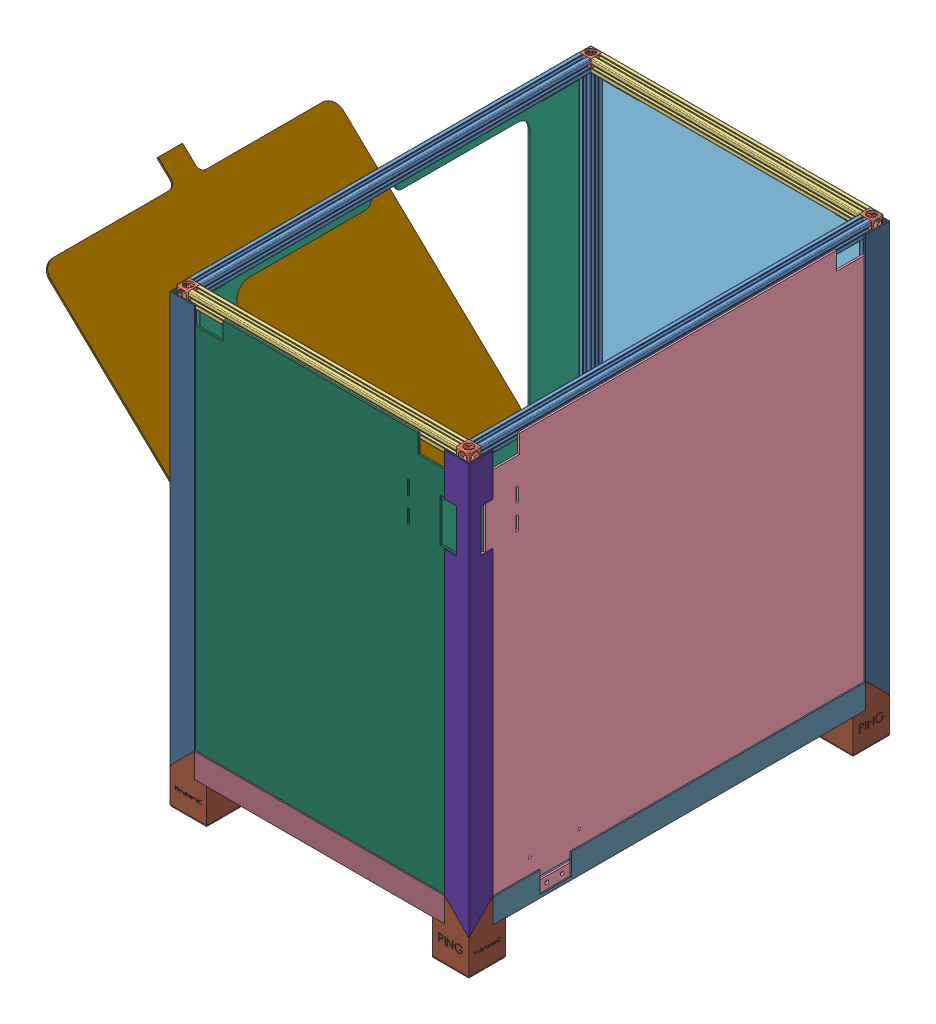
SolidWorks assembly carcasse, configuration Défaut. Lengths in mm.
Overall size (836.58 948 690).
62 component instances, 26 part files, 77 mates.
Components (placement in the parent):
- cadre-1: cadre [Défaut] at (-215.194 -19.8636 -400) size (480 20 680)
  - prof_20x20x600mm-1: prof_20x20x600mm [End Finishing_Non-Machined End Finish Options_Type_Single_] at (-14.8937 4.0689 600) size (20 20 640)
  - Blocks-1: Blocks [Défaut] at (-4.8937 14.0689 1240) x (0 1 0) z (0 0 1) size (20 20 20)
  - prof_20x20x600mm-3: prof_20x20x600mm [End Finishing_Non-Machined End Finish Options_Type_Single_] at (445.1063 4.0689 600) size (20 20 640)
  - Blocks-3: Blocks [Défaut] at (-4.8937 -5.9311 580) x (0 0 -1) z (0 1 0) size (20 20 20)
  - Blocks-4: Blocks [Défaut] at (435.1063 14.0689 600) x (0 1 0) z (0 0 -1) size (20 20 20)
  - Blocks-5: Blocks [Défaut] at (435.1063 -5.9311 1260) x (0 0 1) z (0 1 0) size (20 20 20)
  - prof_20x20x400mm-1: prof_20x20x400mm [End Finishing_Non-Machined End Finish Options_Type_Single_] at (435.1063 4.0689 590) x (0 0 1) z (-1 0 0) size (20 20 440)
  - prof_20x20x400mm-2: prof_20x20x400mm [End Finishing_Non-Machined End Finish Options_Type_Single_] at (435.1063 4.0689 1250) x (0 0 1) z (-1 0 0) size (20 20 440)
- prof_20x20x600mm-1: prof_20x20x600mm [End Finishing_Non-Machined End Finish Options_Type_Single_] at (229.9123 -25.7947 190) x (1 0 0) z (0 -1 0) size (20 20 640)
- prof_20x20x600mm-2: prof_20x20x600mm [End Finishing_Non-Machined End Finish Options_Type_Single_] at (229.9123 -25.7947 850) x (1 0 0) z (0 -1 0) size (20 20 640)
- prof_20x20x600mm-3: prof_20x20x600mm [End Finishing_Non-Machined End Finish Options_Type_Single_] at (-230.0877 -25.7947 850) x (1 0 0) z (0 -1 0) size (20 20 640)
- prof_20x20x600mm-4: prof_20x20x600mm [End Finishing_Non-Machined End Finish Options_Type_Single_] at (-230.0877 -25.7947 190) x (1 0 0) z (0 -1 0) size (20 20 640)
- cadre-2: cadre [Défaut] at (215.0186 -671.7258 -400) x (-1 0 0) z (0 0 1) size (480 20 680)
  - prof_20x20x600mm-1: prof_20x20x600mm [End Finishing_Non-Machined End Finish Options_Type_Single_] at (-14.8937 4.0689 600) size (20 20 640)
  - Blocks-1: Blocks [Défaut] at (-4.8937 14.0689 1240) x (0 1 0) z (0 0 1) size (20 20 20)
  - prof_20x20x600mm-3: prof_20x20x600mm [End Finishing_Non-Machined End Finish Options_Type_Single_] at (445.1063 4.0689 600) size (20 20 640)
  - Blocks-3: Blocks [Défaut] at (-4.8937 -5.9311 580) x (0 0 -1) z (0 1 0) size (20 20 20)
  - Blocks-4: Blocks [Défaut] at (435.1063 14.0689 600) x (0 1 0) z (0 0 -1) size (20 20 20)
  - Blocks-5: Blocks [Défaut] at (435.1063 -5.9311 1260) x (0 0 1) z (0 1 0) size (20 20 20)
  - prof_20x20x400mm-1: prof_20x20x400mm [End Finishing_Non-Machined End Finish Options_Type_Single_] at (435.1063 4.0689 590) x (0 0 1) z (-1 0 0) size (20 20 440)
  - prof_20x20x400mm-2: prof_20x20x400mm [End Finishing_Non-Machined End Finish Options_Type_Single_] at (435.1063 4.0689 1250) x (0 0 1) z (-1 0 0) size (20 20 440)
- plaque_acrylique_680x670-2: plaque_acrylique_680x670 [Défaut] at (239.9123 -350.7947 520) x (0 0 -1) z (1 0 0) size (680 670 3)
- plaque_acrylique_380x670_G-1: plaque_acrylique_380x670_G [Défaut] at (49.9123 -350.7947 177) size (480 670 3)
- plaque_acrylique_680x670_porte-1: plaque_acrylique_680x670_porte [Défaut] at (-243.0877 -350.7947 520) x (0 0 -1) z (1 0 0) size (680 670 3)
- charniere-1: charniere [Défaut] at (-236.7309 -495.7947 776.2875) x (0 0 1) z (0 -1 0) size (40 29.08 53.23)
  - axe charnière-1: axe charnière [Défaut] at (-76.2875 9.8568 0) size (40 5 5)
  - batant charnière-1: batant charnière [Défaut] at (-76.2875 10.1991 -17.6196) size (40 7 33.5)
  - batant charnière-2: batant charnière [Défaut] at (-36.2875 -2.6626 12.4029) x (-1 0 0) z (0 0.723942 -0.689861) size (40 7 33.5)
- charniere-2: charniere [Défaut] at (-236.7309 -495.7947 376.2875) x (0 0 1) z (0 -1 0) size (40 29.08 53.23)
  - axe charnière-1: axe charnière [Défaut] at (-76.2875 9.8568 0) size (40 5 5)
  - batant charnière-1: batant charnière [Défaut] at (-76.2875 10.1991 -17.6196) size (40 7 33.5)
  - batant charnière-2: batant charnière [Défaut] at (-36.2875 -2.6626 12.4029) x (-1 0 0) z (0 0.723942 -0.689861) size (40 7 33.5)
- porte-1: porte [Défaut] at (-349.1448 -393.231 520) x (0 0 -1) z (0.689861 0.723942 0) size (480 480 3)
- eclisse_40x40x670_bisote_x1-1: eclisse_40x40x670_bisote_x1 [Défaut] at (-225.0877 -688.7947 195.1136) size (40 673 40)
- eclisse_40x40x670_bisote_x1-2: eclisse_40x40x670_bisote_x1 [Défaut] at (-224.9741 -688.7947 845) x (0 0 -1) z (1 0 0) size (40 673 40)
- eclisse_40x40x670_bisote_x1-4: eclisse_40x40x670_bisote_x1 [Défaut] at (224.7986 -688.7947 195) x (0 0 1) z (-1 0 0) size (40 673 40)
- couvercle-1: couvercle [Défaut] at (451.7811 15.2953 693.3892) size (490 215 690) (hidden)
  - plaque_acrylique_680x210-2: plaque_acrylique_680x210 [Défaut] at (-694.8689 73.91 -173.3892) x (0 0 -1) z (1 0 0) size (680 210 3)
  - plaque_acrylique_380x210-2: plaque_acrylique_380x210 [Défaut] at (-401.8689 73.91 -516.3892) size (480 210 3)
  - plaque_acrylique_380x680-1: plaque_acrylique_380x680 [Défaut] at (-401.8689 178.91 -173.3892) x (1 0 0) z (0 1 0) size (480 680 3)
  - eclisse_40x40x404_bisote_x2-1: eclisse_40x40x404_bisote_x2 [Défaut] at (-206.8689 163.7964 -498.3892) x (0 0 1) z (0 -1 0) size (40 490 40)
  - eclisse_40x40x704_bisote_x2-1: eclisse_40x40x704_bisote_x2 [Défaut] at (-226.9825 163.91 -518.3892) x (0 -1 0) z (-1 0 0) size (40 690 40)
  - eclisse_40x40x404_bisote_x2-2: eclisse_40x40x404_bisote_x2 [Défaut] at (-696.8689 163.7964 151.6108) x (0 0 -1) z (0 -1 0) size (40 490 40)
  - eclisse_40x40x704_bisote_x2-2: eclisse_40x40x704_bisote_x2 [Défaut] at (-676.8689 163.7964 -518.3892) x (1 0 0) z (0 -1 0) size (40 690 40)
  - eclisse_40x40x222_bisote_x1-1: eclisse_40x40x222_bisote_x1 [Défaut] at (-676.7552 183.91 -498.3892) x (0 0 1) z (1 0 0) size (40 215 40)
  - eclisse_40x40x222_bisote_x1-2: eclisse_40x40x222_bisote_x1 [Défaut] at (-226.8689 183.91 -498.2755) x (-1 0 0) z (0 0 1) size (40 215 40)
  - eclisse_40x40x222_bisote_x1-4: eclisse_40x40x222_bisote_x1 [Défaut] at (-676.8689 183.91 151.4972) x (1 0 0) z (0 0 -1) size (40 215 40)
  - plaque_acrylique_380x210_Moteur-1: plaque_acrylique_380x210_Moteur [Défaut] at (-401.8689 73.91 166.6108) size (480 210 3)
  - plaque_acrylique_680x210_moteur-1: plaque_acrylique_680x210_moteur [Défaut] at (-211.8689 73.91 -173.3892) x (0 0 -1) z (1 0 0) size (680 210 3)
  - eclisse_40x40x222_bisote_x1_Moteur-1: eclisse_40x40x222_bisote_x1_Moteur [Défaut] at (-226.9825 183.91 151.6108) x (0 0 -1) z (-1 0 0) size (40 215 40)
- Pied-1: Pied [Défaut] at (184.9123 -688.7947 235) x (-1 0 0) z (0 -1 0) size (60 60 100)
- Pied-2: Pied [Défaut] at (184.9123 -688.7947 805) x (0 0 -1) z (0 -1 0) size (60 60 100)
- Pied-3: Pied [Défaut] at (-185.0877 -688.7947 805) x (1 0 0) z (0 -1 0) size (60 60 100)
- Pied-4: Pied [Défaut] at (-185.0877 -688.7947 235) x (0 0 1) z (0 -1 0) size (60 60 100)
- eclisse_bas_40x40x704-2: eclisse_bas_40x40x704 [Défaut] at (-225.0877 -670.681 825) x (1 0 0) z (0 1 0) size (40 610 40)
- eclisse_bas_40x40x404-1: eclisse_bas_40x40x404 [Défaut] at (-205.0877 -670.681 195) x (0 0 1) z (0 1 0) size (40 410 40)
- eclisse_bas_40x40x404-2: eclisse_bas_40x40x404 [Défaut] at (204.9123 -668.681 845) x (0 0 -1) z (0 1 0) size (40 410 40)
- eclisse_bas_support_Z_40x40x704-1: eclisse_bas_support_Z_40x40x704 [Défaut] at (224.7986 -670.7947 825) x (0 1 0) z (-1 0 0) size (40 610 40)
- plaque_acrylique_380x670_D-2: plaque_acrylique_380x670_D [Défaut] at (-50.0877 -350.7947 863) x (-1 0 0) z (0 0 -1) size (480 670 3)
- plaque_acrylique_bas_380x680-1: plaque_acrylique_bas_380x680 [Défaut] at (49.9123 -688.7947 520) x (1 0 0) z (0 1 0) size (480 680 3)
- eclisse_40x40x670_bisote_x1-Moteur-1: eclisse_40x40x670_bisote_x1-Moteur [Défaut] at (224.9123 -688.7947 844.8864) x (-1 0 0) z (0 0 -1) size (40 673 40)
Mates (geometry in assembly coordinates):
- Coïncidente50: coincident anti-aligned: plane of plaque_acrylique_680x670_porte-1 through (-243.0877 -350.7947 520) normal (-1 0 0); plane of charniere-1/batant charnière-1 through (-243.0877 -535.7947 740) normal (1 0 0)
- Coïncidente51: coincident anti-aligned: plane of plaque_acrylique_680x670_porte-1 through (-243.0877 -350.7947 520) normal (-1 0 0); plane of charniere-2/batant charnière-1 through (-243.0877 -535.7947 340) normal (1 0 0)
- Distance4: distance = 20 mm anti-aligned: plane of charniere-2/batant charnière-1 through (-246.5877 -495.7947 300) normal (0 0 -1); plane of plaque_acrylique_680x670_porte-1 through (-243.0877 -75.7947 280) normal (0 0 1)
- Coïncidente54: coincident aligned: line of plaque_acrylique_680x670_porte-1 through (-243.0877 -495.7947 740) axis (0 0 -1); line of charniere-2/batant charnière-1 through (-243.0877 -495.7947 340) axis (0 0 -1)
- Distance5: distance = 20 mm anti-aligned: plane of plaque_acrylique_680x670_porte-1 through (-243.0877 -75.7947 760) normal (0 0 -1); plane of charniere-1/batant charnière-1 through (-246.5877 -495.7947 740) normal (0 0 1)
- Coïncidente57: coincident aligned: line of plaque_acrylique_680x670_porte-1 through (-243.0877 -495.7947 740) axis (0 0 -1); line of charniere-1/batant charnière-1 through (-243.0877 -495.7947 740) axis (0 0 -1)
- Coïncidente62: coincident anti-aligned: plane of charniere-1/batant charnière-2 through (-273.1309 -465.6664 700) normal (0.689861 0.723942 0); plane of porte-1 through (-569.947 -182.8234 550) normal (-0.689861 -0.723942 0)
- Coïncidente63: coincident anti-aligned: line of charniere-1/batant charnière-2 through (-244.1732 -493.2609 720) axis (0 0 1); line of porte-1 through (-244.1732 -493.2609 740) axis (0 0 -1)
- Coïncidente64: coincident anti-aligned: plane of plaque_acrylique_680x670_porte-1 through (-243.0877 -75.7947 760) normal (0 0 -1); plane of porte-1 through (-546.1592 -201.3474 760) normal (0 0 1)
- Coïncidente66: coincident anti-aligned: plane of plaque_acrylique_680x670_porte-1 through (-243.0877 -350.7947 520) normal (-1 0 0); plane of eclisse_40x40x670_bisote_x1-1 through (-243.0877 -15.7947 177) normal (1 0 0)
- Coïncidente67: coincident aligned: plane of plaque_acrylique_680x670_porte-1 through (-240.0877 -15.7947 860) normal (0 1 0); plane of eclisse_40x40x670_bisote_x1-1 through (-225.0877 -15.7947 195.1136) normal (0 1 0)
- Coïncidente68: coincident anti-aligned: plane of plaque_acrylique_680x670-2 through (242.9123 -350.7947 520) normal (1 0 0); plane of eclisse_40x40x670_bisote_x1-4 through (242.9123 -15.7947 177) normal (-1 0 0)
- Coïncidente72: coincident anti-aligned: plane of plaque_acrylique_680x670_porte-1 through (-243.0877 -350.7947 520) normal (-1 0 0); plane of eclisse_40x40x670_bisote_x1-2 through (-243.0877 -15.7947 863) normal (1 0 0)
- Coïncidente100: coincident: plane of plaque_acrylique_680x670_porte-1 through (-240.0877 -15.7947 860) normal (0 1 0); line of eclisse_40x40x670_bisote_x1-2 through (-243.0877 -15.7947 863) axis (0 0 -1)
- Coïncidente130: coincident anti-aligned: plane of eclisse_40x40x670_bisote_x1-2 through (344.9123 -688.7947 865) normal (0 -0.707107 -0.707107); plane of Pied-3 through (-243.0877 -648.7947 825) normal (0 0.707107 0.707107)
- Coïncidente132: coincident anti-aligned: plane of plaque_acrylique_680x670_porte-1 through (-243.0877 -350.7947 520) normal (-1 0 0); plane of eclisse_bas_40x40x704-2 through (-243.0877 -688.7947 215) normal (1 0 0)
- Coïncidente134: coincident anti-aligned: line of eclisse_40x40x670_bisote_x1-2 through (-245.0877 -15.7947 825) axis (0 -1 0); line of eclisse_bas_40x40x704-2 through (-245.0877 -690.7947 825) axis (0 1 0)
- Coïncidente140: coincident anti-aligned: line of Pied-3 through (-205.0877 -648.7947 865) axis (0 -1 0); line of eclisse_bas_40x40x404-2 through (-205.0877 -688.7947 865) axis (0 1 0)
- Coïncidente142: coincident anti-aligned: plane of plaque_acrylique_680x670-2 through (242.9123 -350.7947 520) normal (1 0 0); plane of eclisse_bas_support_Z_40x40x704-1 through (242.9123 -688.7947 215) normal (-1 0 0)
- Coïncidente144: coincident anti-aligned: plane of Pied-2 through (242.9123 -648.7947 825) normal (0 0 -1); plane of eclisse_bas_support_Z_40x40x704-1 through (224.7986 -670.7947 825) normal (0 0 1)
- Coïncidente151: coincident anti-aligned: plane of Pied-3 through (-185.0877 -688.7947 805) normal (0 1 0); plane of eclisse_bas_40x40x404-2 through (-205.0877 -688.7947 865) normal (0 -1 0)
- Coïncidente156: coincident anti-aligned: plane of eclisse_bas_40x40x404-2 through (-205.0877 -686.7947 863) normal (0 0 -1); plane of plaque_acrylique_380x670_D-2 through (-50.0877 -350.7947 863) normal (0 0 1)
- Coïncidente157: coincident anti-aligned: plane of eclisse_40x40x670_bisote_x1-2 through (-243.0877 -15.7947 863) normal (0 0 -1); plane of plaque_acrylique_380x670_D-2 through (-50.0877 -350.7947 863) normal (0 0 1)
- Coïncidente163: coincident anti-aligned: plane of cadre-1/Blocks-1 through (-240.0877 -25.7947 860) normal (0 -1 0); plane of prof_20x20x600mm-3 through (-238.5877 -25.7947 858.5) normal (0 1 0)
- Coïncidente164: coincident aligned: plane of cadre-1/Blocks-1 through (-240.0877 -25.7947 860) normal (-1 0 0); plane of prof_20x20x600mm-3 through (-240.0877 -665.7947 853.75) normal (-1 0 0)
- Coïncidente165: coincident aligned: plane of cadre-1/Blocks-1 through (-220.0877 -5.7947 860) normal (0 0 1); plane of prof_20x20x600mm-3 through (-233.8377 -665.7947 860) normal (0 0 1)
- Coïncidente166: coincident anti-aligned: plane of prof_20x20x600mm-3 through (-238.5877 -665.7947 858.5) normal (0 -1 0); plane of cadre-2/Blocks-5 through (-220.0877 -665.7947 860) normal (0 1 0)
- Coïncidente167: coincident aligned: plane of prof_20x20x600mm-3 through (-233.8377 -665.7947 860) normal (0 0 1); plane of cadre-2/Blocks-5 through (-240.0877 -685.7947 860) normal (0 0 1)
- Coïncidente168: coincident aligned: plane of prof_20x20x600mm-3 through (-240.0877 -665.7947 853.75) normal (-1 0 0); plane of cadre-2/Blocks-5 through (-240.0877 -685.7947 840) normal (-1 0 0)
- Coïncidente169: coincident anti-aligned: plane of prof_20x20x600mm-2 through (221.4123 -665.7947 858.5) normal (0 -1 0); plane of cadre-2/Blocks-1 through (239.9123 -665.7947 860) normal (0 1 0)
- Coïncidente170: coincident aligned: plane of prof_20x20x600mm-2 through (226.1623 -665.7947 860) normal (0 0 1); plane of cadre-2/Blocks-1 through (219.9123 -685.7947 860) normal (0 0 1)
- Coïncidente171: coincident aligned: plane of prof_20x20x600mm-2 through (239.9123 -665.7947 853.75) normal (1 0 0); plane of cadre-2/Blocks-1 through (239.9123 -665.7947 860) normal (1 0 0)
- Coïncidente172: coincident anti-aligned: plane of prof_20x20x600mm-1 through (221.4123 -665.7947 198.5) normal (0 -1 0); plane of cadre-2/Blocks-3 through (219.9123 -665.7947 180) normal (0 1 0)
- Coïncidente173: coincident aligned: plane of prof_20x20x600mm-1 through (239.9123 -665.7947 193.75) normal (1 0 0); plane of cadre-2/Blocks-3 through (239.9123 -685.7947 200) normal (1 0 0)
- Coïncidente174: coincident aligned: plane of prof_20x20x600mm-1 through (233.6623 -665.7947 180) normal (0 0 -1); plane of cadre-2/Blocks-3 through (239.9123 -685.7947 180) normal (0 0 -1)
- Coïncidente175: coincident aligned: plane of cadre-1/Blocks-3 through (-240.0877 -5.7947 200) normal (-1 0 0); plane of prof_20x20x600mm-4 through (-240.0877 -665.7947 186.25) normal (-1 0 0)
- Coïncidente176: coincident aligned: plane of cadre-1/Blocks-3 through (-240.0877 -5.7947 180) normal (0 0 -1); plane of prof_20x20x600mm-4 through (-233.8377 -665.7947 180) normal (0 0 -1)
- Coïncidente177: coincident anti-aligned: plane of cadre-1/Blocks-3 through (-220.0877 -25.7947 180) normal (0 -1 0); plane of prof_20x20x600mm-4 through (-238.5877 -25.7947 198.5) normal (0 1 0)
- Coïncidente183: coincident aligned: plane of prof_20x20x600mm-2 through (239.9123 -665.7947 853.75) normal (1 0 0); plane of plaque_acrylique_380x670_D-2 through (239.9123 -15.7947 860) normal (1 0 0)
- Coïncidente185: coincident anti-aligned: plane of cadre-1/prof_20x20x600mm-3 through (239.9123 -12.0447 840) normal (1 0 0); plane of plaque_acrylique_680x670-2 through (239.9123 -350.7947 520) normal (-1 0 0)
- Coïncidente186: coincident aligned: plane of cadre-1/prof_20x20x400mm-2 through (-220.0877 -12.0447 860) normal (0 0 1); plane of plaque_acrylique_680x670-2 through (242.9123 -15.7947 860) normal (0 0 1)
- Coïncidente187: coincident aligned: plane of cadre-1/prof_20x20x400mm-1 through (-220.0877 -19.5447 180) normal (0 0 -1); plane of plaque_acrylique_680x670_porte-1 through (-240.0877 -15.7947 180) normal (0 0 -1)
- Coïncidente191: coincident anti-aligned: plane of cadre-2/prof_20x20x400mm-1 through (219.9123 -685.7947 193.75) normal (0 -1 0); plane of plaque_acrylique_bas_380x680-1 through (49.9123 -685.7947 520) normal (0 1 0)
- Coïncidente192: coincident aligned: plane of cadre-2/prof_20x20x400mm-2 through (219.9123 -679.5447 860) normal (0 0 1); plane of plaque_acrylique_bas_380x680-1 through (-240.0877 -685.7947 860) normal (0 0 1)
- Coïncidente193: coincident aligned: plane of cadre-2/prof_20x20x600mm-1 through (239.9123 -679.5447 840) normal (1 0 0); plane of plaque_acrylique_bas_380x680-1 through (239.9123 -685.7947 180) normal (1 0 0)
- Coïncidente195: coincident anti-aligned: plane of Pied-2 through (184.9123 -688.7947 805) normal (0 1 0); plane of plaque_acrylique_bas_380x680-1 through (49.9123 -688.7947 520) normal (0 -1 0)
- Coïncidente198: coincident anti-aligned: plane of Pied-1 through (184.9123 -688.7947 235) normal (0 1 0); plane of plaque_acrylique_bas_380x680-1 through (49.9123 -688.7947 520) normal (0 -1 0)
- Coïncidente199: coincident anti-aligned: line of eclisse_40x40x670_bisote_x1-4 through (244.9123 -688.7947 175) axis (0 0.707107 0.707107); line of Pied-1 through (244.9123 -648.7947 215) axis (0 -0.707107 -0.707107)
- Coïncidente200: coincident anti-aligned: plane of Pied-2 through (184.9123 -688.7947 805) normal (0 1 0); plane of plaque_acrylique_bas_380x680-1 through (49.9123 -688.7947 520) normal (0 -1 0)
- Coïncidente201: coincident anti-aligned: plane of plaque_acrylique_680x670-2 through (242.9123 -350.7947 520) normal (1 0 0); plane of Pied-2 through (242.9123 -648.7947 863) normal (-1 0 0)
- Coïncidente203: coincident aligned: plane of cadre-2/prof_20x20x600mm-3 through (-233.8377 -685.7947 840) normal (0 -1 0); plane of plaque_acrylique_680x670_porte-1 through (-240.0877 -685.7947 860) normal (0 -1 0)
- Coïncidente204: coincident anti-aligned: plane of prof_20x20x600mm-1 through (233.6623 -665.7947 180) normal (0 0 -1); plane of plaque_acrylique_380x670_G-1 through (49.9123 -350.7947 180) normal (0 0 1)
- Coïncidente205: coincident aligned: plane of cadre-2/prof_20x20x400mm-1 through (219.9123 -685.7947 186.25) normal (0 -1 0); plane of plaque_acrylique_380x670_G-1 through (-240.0877 -685.7947 180) normal (0 -1 0)
- Coïncidente206: coincident aligned: plane of prof_20x20x600mm-1 through (239.9123 -665.7947 186.25) normal (1 0 0); plane of plaque_acrylique_380x670_G-1 through (239.9123 -15.7947 180) normal (1 0 0)
- Coïncidente207: coincident anti-aligned: plane of prof_20x20x600mm-4 through (-240.0877 -665.7947 186.25) normal (-1 0 0); plane of plaque_acrylique_680x670_porte-1 through (-240.0877 -350.7947 520) normal (1 0 0)
- Coïncidente208: coincident anti-aligned: plane of plaque_acrylique_380x670_G-1 through (49.9123 -350.7947 177) normal (0 0 -1); plane of eclisse_40x40x670_bisote_x1-1 through (-243.0877 -15.7947 177) normal (0 0 1)
- Coïncidente210: coincident anti-aligned: plane of plaque_acrylique_380x670_G-1 through (49.9123 -350.7947 177) normal (0 0 -1); plane of eclisse_40x40x670_bisote_x1-4 through (242.9123 -15.7947 177) normal (0 0 1)
- Coïncidente211: coincident anti-aligned: plane of Pied-4 through (-185.0877 -688.7947 235) normal (0 1 0); plane of plaque_acrylique_bas_380x680-1 through (49.9123 -688.7947 520) normal (0 -1 0)
- Parallèle4: parallel anti-aligned: line of eclisse_40x40x670_bisote_x1-1 through (-245.0877 -688.7947 175) axis (0.707107 0.707107 0); line of Pied-4 through (-205.0877 -648.7947 175) axis (-0.707107 -0.707107 0)
- Coïncidente217: coincident aligned: plane of cadre-2/prof_20x20x600mm-1 through (233.6623 -685.7947 840) normal (0 -1 0); plane of plaque_acrylique_680x670-2 through (242.9123 -685.7947 860) normal (0 -1 0)
- Coïncidente218: coincident: plane of cadre-2/prof_20x20x400mm-2 through (219.9123 -685.7947 853.75) normal (0 -1 0); line of plaque_acrylique_380x670_D-2 through (239.9123 -685.7947 863) axis (-1 0 0)
- Coïncidente223: coincident anti-aligned: plane of eclisse_bas_support_Z_40x40x704-1 through (242.9123 -688.7947 215) normal (0 1 0); plane of plaque_acrylique_bas_380x680-1 through (49.9123 -688.7947 520) normal (0 -1 0)
- Coïncidente224: coincident anti-aligned: plane of eclisse_bas_40x40x704-2 through (-243.0877 -688.7947 215) normal (0 1 0); plane of plaque_acrylique_bas_380x680-1 through (49.9123 -688.7947 520) normal (0 -1 0)
- Coïncidente225: coincident anti-aligned: plane of plaque_acrylique_380x670_G-1 through (49.9123 -350.7947 177) normal (0 0 -1); plane of eclisse_bas_40x40x404-1 through (204.9123 -688.7947 177) normal (0 0 1)
- Coïncidente226: coincident anti-aligned: plane of eclisse_bas_40x40x404-1 through (204.9123 -688.7947 177) normal (0 1 0); plane of plaque_acrylique_bas_380x680-1 through (49.9123 -688.7947 520) normal (0 -1 0)
- Coïncidente227: coincident anti-aligned: plane of Pied-1 through (204.9123 -648.7947 177) normal (-1 0 0); plane of eclisse_bas_40x40x404-1 through (204.9123 -670.681 195) normal (1 0 0)
- Coïncidente228: coincident anti-aligned: plane of plaque_acrylique_680x670_porte-1 through (-243.0877 -350.7947 520) normal (-1 0 0); plane of Pied-3 through (-243.0877 -648.7947 825) normal (1 0 0)
- Coïncidente229: coincident anti-aligned: plane of plaque_acrylique_380x670_G-1 through (49.9123 -350.7947 177) normal (0 0 -1); plane of Pied-4 through (-205.0877 -648.7947 177) normal (0 0 1)
- Coïncidente230: coincident anti-aligned: plane of plaque_acrylique_680x670_porte-1 through (-243.0877 -350.7947 520) normal (-1 0 0); plane of Pied-4 through (-243.0877 -648.7947 177) normal (1 0 0)
- Coïncidente231: coincident anti-aligned: plane of plaque_acrylique_380x670_G-1 through (49.9123 -350.7947 177) normal (0 0 -1); plane of Pied-1 through (242.9123 -648.7947 177) normal (0 0 1)
- Coïncidente232: coincident aligned: plane of plaque_acrylique_380x670_G-1 through (49.9123 -350.7947 177) normal (0 0 -1); plane of couvercle-1/plaque_acrylique_380x210-2 through (49.9123 89.2053 177) normal (0 0 -1)
- Coïncidente233: coincident aligned: plane of couvercle-1/plaque_acrylique_380x210_Moteur-1 through (49.9123 89.2053 863) normal (0 0 1); plane of plaque_acrylique_380x670_D-2 through (-50.0877 -350.7947 863) normal (0 0 1)
- Coïncidente234: coincident anti-aligned: line of plaque_acrylique_680x670-2 through (242.9123 -15.7947 260) axis (0 0 1); line of couvercle-1/plaque_acrylique_680x210_moteur-1 through (242.9123 -15.7947 780) axis (0 0 -1)
- Coïncidente235: coincident aligned: plane of plaque_acrylique_680x670-2 through (242.9123 -350.7947 520) normal (1 0 0); plane of couvercle-1/plaque_acrylique_680x210_moteur-1 through (242.9123 89.2053 520) normal (1 0 0)
- Coïncidente236: coincident anti-aligned: plane of plaque_acrylique_680x670-2 through (242.9123 -350.7947 520) normal (1 0 0); plane of eclisse_40x40x670_bisote_x1-Moteur-1 through (242.9123 -15.7947 863) normal (-1 0 0)
- Coïncidente237: coincident anti-aligned: plane of plaque_acrylique_380x670_D-2 through (-50.0877 -350.7947 863) normal (0 0 1); plane of eclisse_40x40x670_bisote_x1-Moteur-1 through (242.9123 -15.7947 863) normal (0 0 -1)
- Coïncidente238: coincident anti-aligned: line of Pied-2 through (204.9123 -648.7947 865) axis (0.707107 -0.707107 0); line of eclisse_40x40x670_bisote_x1-Moteur-1 through (244.9123 -688.7947 865) axis (-0.707107 0.707107 0)
